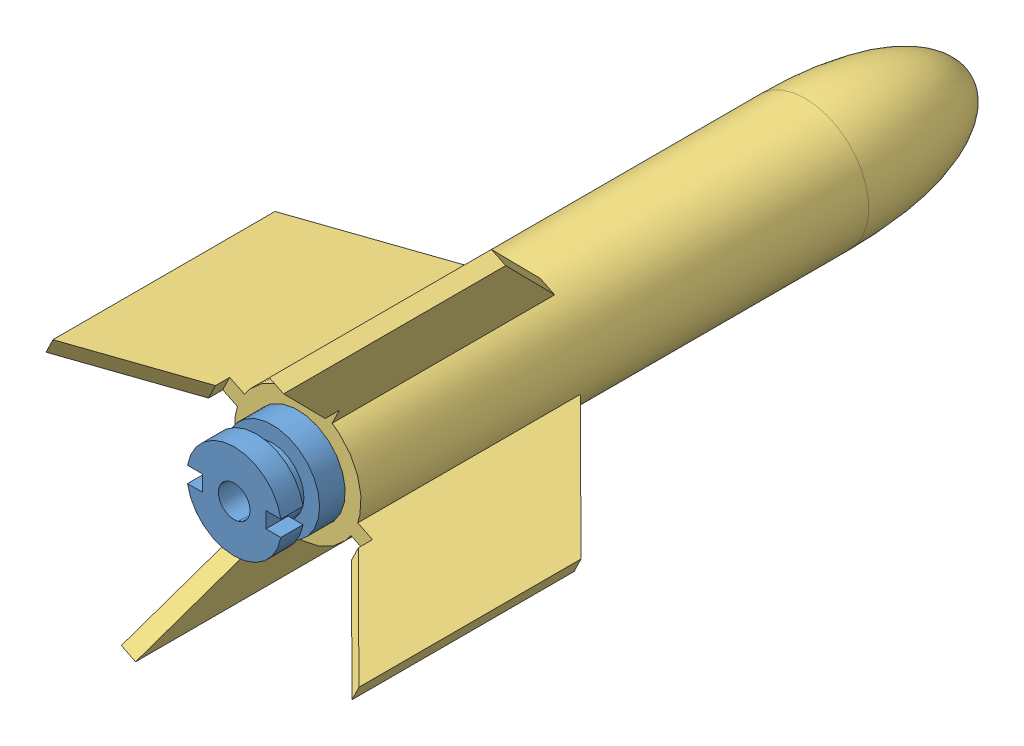
SolidWorks assembly Torpedo, configuration Default. Lengths in mm.
Overall size (90.86 90.86 152.5).
3 component instances, 3 part files, 6 mates.
Components (placement in the parent):
- Pressure Vessel-1: Pressure Vessel [Default] at (71.0407 89.3516 69.334) size (19.05 19.05 114.3)
- 8063K170_AIR FILL VALVE-1: 8063K170_AIR FILL VALVE [8063K17] at (71.0407 89.3516 80.4465) x (-0.222419 0.974951 0) z (-0.974951 -0.222419 0) size (14.29 33.45 16.5)
- Shell-1: Shell [Default] at (71.0407 89.3516 170.934) x (-0.900265 0.435343 0) z (0 0 -1) size (68.03 68.03 152.5)
Mates (geometry in assembly coordinates):
- Concentric1: concentric anti-aligned: cylinder of Pressure Vessel-1 through (71.0407 89.3516 199.3494) axis (0 0 -1) radius 5.5563; cylinder of 8063K210_AIR FILL VALVE-1 through (71.0407 89.3516 39.7815) axis (0 0 1) radius 1.9304
- Concentric2: concentric anti-aligned: cylinder of Pressure Vessel-1 through (71.0407 89.3516 199.3494) axis (0 0 -1) radius 5.5563; cylinder of 8063K170_AIR FILL VALVE-1 through (71.0407 89.3516 55.0465) axis (0 0 1) radius 1.9304
- Concentric3: concentric anti-aligned: cylinder of Pressure Vessel-1 through (71.0407 89.3516 199.3494) axis (0 0 -1) radius 5.5563; cylinder of 8063K170_AIR FILL VALVE-1 through (71.0407 89.3516 55.0465) axis (0 0 1) radius 1.9304
- Coincident1: coincident anti-aligned: plane of Pressure Vessel-1 through (71.0407 89.3516 69.334) normal (0 0 -1); plane of 8063K170_AIR FILL VALVE-1 through (71.0407 89.3516 69.334) normal (0 0 1)
- Concentric4: concentric anti-aligned: cylinder of Pressure Vessel-1 through (71.0407 89.3516 183.634) axis (0 0 -1) radius 9.525; cylinder of Shell-1 through (71.0407 89.3516 69.334) axis (0 0 1) radius 9.525
- Coincident2: coincident aligned: plane of Pressure Vessel-1 through (71.0407 89.3516 69.334) normal (0 0 -1); circle of Shell-1
